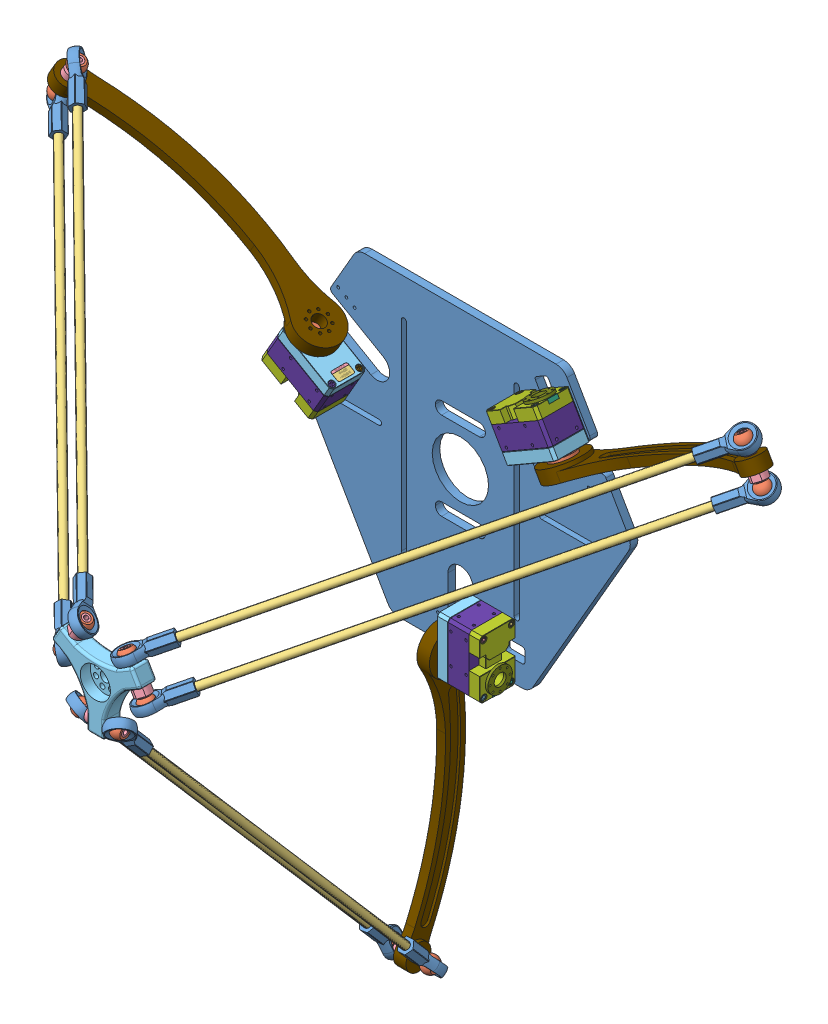
SolidWorks assembly Mat_1, configuration Default. Lengths in mm.
Overall size (587.7 511.52 315.27).
95 component instances, 23 part files, 90 mates.
Components (placement in the parent):
- base_XM430-1: base_XM430 [Default] at (94.6389 179.5874 188.3859) size (271.39 237.71 6)
- XM430-W350-R-1: XM430-W350-R [Default] at (171.6275 254.5304 208.1491) x (0 0 -1) z (0.5 -0.866025 0) size (28.5 46.5 41)
  - XM430-W350-R.step-1: XM430-W350-R.step [Default] at origin size (28.5 46.5 41)
    - Part 1.step-1: Part 1.step [Default] at (-0.4867 -0.6755 -0.5918) size (19.5 19.5 4)
    - Part 2.step-1: Part 2.step [Default] at (-0.4867 -0.6755 -0.5918) size (13.3 5.9 0.1)
    - Part 3.step-1: Part 3.step [Default] at (-0.4867 -0.6755 -0.5918) size (13.3 1.9 0.1)
    - Part 4.step-1: Part 4.step [Default] at (-0.4867 -0.6755 -0.5918) size (28.5 46.5 8.5)
    - Part 5.step-1: Part 5.step [Default] at (-0.4867 -0.6755 -0.5918) size (8 1.5 3)
    - Part 6.step-1: Part 6.step [Default] at (-0.4867 -0.6755 -0.5918) size (28.5 46.5 8.5)
    - Part 7.step-1: Part 7.step [Default] at (-0.4867 -0.6755 -0.5918) size (4 4 3.8)
    - Part 8.step-1: Part 8.step [Default] at (-0.4867 -0.6755 -0.5918) size (4 4 3.8)
    - Part 9.step-1: Part 9.step [Default] at (-0.4867 -0.6755 -0.5918) size (4 4 3.8)
    - Part 10.step-1: Part 10.step [Default] at (-0.4867 -0.6755 -0.5918) size (4 4 3.8)
    - Part 11.step-1: Part 11.step [Default] at (-0.4867 -0.6755 -0.5918) size (4 4 3.8)
    - Part 12.step-1: Part 12.step [Default] at (-0.4867 -0.6755 -0.5918) size (4 4 3.8)
    - Part 13.step-1: Part 13.step [Default] at (-0.4867 -0.6755 -0.5918) size (4 4 3.8)
    - Part 14.step-1: Part 14.step [Default] at (-0.4867 -0.6755 -0.5918) size (4 4 3.8)
    - Part 15.step-1: Part 15.step [Default] at (-0.4867 -0.6755 -0.5918) size (19.5 19.5 2)
    - Part 16.step-1: Part 16.step [Default] at (-0.4867 -0.6755 -0.5918) size (28.5 46.5 17)
- XM430-W350-R-2: XM430-W350-R [Default] at (-8.7579 208.79 208.1491) x (0 0 -1) z (0.5 0.866025 0) size (28.5 46.5 41)
  - XM430-W350-R.step-1: XM430-W350-R.step [Default] at origin size (28.5 46.5 41)
    - Part 1.step-1: Part 1.step [Default] at (-0.4867 -0.6755 -0.5918) size (19.5 19.5 4)
    - Part 2.step-1: Part 2.step [Default] at (-0.4867 -0.6755 -0.5918) size (13.3 5.9 0.1)
    - Part 3.step-1: Part 3.step [Default] at (-0.4867 -0.6755 -0.5918) size (13.3 1.9 0.1)
    - Part 4.step-1: Part 4.step [Default] at (-0.4867 -0.6755 -0.5918) size (28.5 46.5 8.5)
    - Part 5.step-1: Part 5.step [Default] at (-0.4867 -0.6755 -0.5918) size (8 1.5 3)
    - Part 6.step-1: Part 6.step [Default] at (-0.4867 -0.6755 -0.5918) size (28.5 46.5 8.5)
    - Part 7.step-1: Part 7.step [Default] at (-0.4867 -0.6755 -0.5918) size (4 4 3.8)
    - Part 8.step-1: Part 8.step [Default] at (-0.4867 -0.6755 -0.5918) size (4 4 3.8)
    - Part 9.step-1: Part 9.step [Default] at (-0.4867 -0.6755 -0.5918) size (4 4 3.8)
    - Part 10.step-1: Part 10.step [Default] at (-0.4867 -0.6755 -0.5918) size (4 4 3.8)
    - Part 11.step-1: Part 11.step [Default] at (-0.4867 -0.6755 -0.5918) size (4 4 3.8)
    - Part 12.step-1: Part 12.step [Default] at (-0.4867 -0.6755 -0.5918) size (4 4 3.8)
    - Part 13.step-1: Part 13.step [Default] at (-0.4867 -0.6755 -0.5918) size (4 4 3.8)
    - Part 14.step-1: Part 14.step [Default] at (-0.4867 -0.6755 -0.5918) size (4 4 3.8)
    - Part 15.step-1: Part 15.step [Default] at (-0.4867 -0.6755 -0.5918) size (19.5 19.5 2)
    - Part 16.step-1: Part 16.step [Default] at (-0.4867 -0.6755 -0.5918) size (28.5 46.5 17)
- XM430-W350-R-3: XM430-W350-R [Default] at (121.0471 75.4419 208.1491) x (0 0 -1) z (-1 0 0) size (28.5 46.5 41)
  - XM430-W350-R.step-1: XM430-W350-R.step [Default] at origin size (28.5 46.5 41)
    - Part 1.step-1: Part 1.step [Default] at (-0.4867 -0.6755 -0.5918) size (19.5 19.5 4)
    - Part 2.step-1: Part 2.step [Default] at (-0.4867 -0.6755 -0.5918) size (13.3 5.9 0.1)
    - Part 3.step-1: Part 3.step [Default] at (-0.4867 -0.6755 -0.5918) size (13.3 1.9 0.1)
    - Part 4.step-1: Part 4.step [Default] at (-0.4867 -0.6755 -0.5918) size (28.5 46.5 8.5)
    - Part 5.step-1: Part 5.step [Default] at (-0.4867 -0.6755 -0.5918) size (8 1.5 3)
    - Part 6.step-1: Part 6.step [Default] at (-0.4867 -0.6755 -0.5918) size (28.5 46.5 8.5)
    - Part 7.step-1: Part 7.step [Default] at (-0.4867 -0.6755 -0.5918) size (4 4 3.8)
    - Part 8.step-1: Part 8.step [Default] at (-0.4867 -0.6755 -0.5918) size (4 4 3.8)
    - Part 9.step-1: Part 9.step [Default] at (-0.4867 -0.6755 -0.5918) size (4 4 3.8)
    - Part 10.step-1: Part 10.step [Default] at (-0.4867 -0.6755 -0.5918) size (4 4 3.8)
    - Part 11.step-1: Part 11.step [Default] at (-0.4867 -0.6755 -0.5918) size (4 4 3.8)
    - Part 12.step-1: Part 12.step [Default] at (-0.4867 -0.6755 -0.5918) size (4 4 3.8)
    - Part 13.step-1: Part 13.step [Default] at (-0.4867 -0.6755 -0.5918) size (4 4 3.8)
    - Part 14.step-1: Part 14.step [Default] at (-0.4867 -0.6755 -0.5918) size (4 4 3.8)
    - Part 15.step-1: Part 15.step [Default] at (-0.4867 -0.6755 -0.5918) size (19.5 19.5 2)
    - Part 16.step-1: Part 16.step [Default] at (-0.4867 -0.6755 -0.5918) size (28.5 46.5 17)
- link1-1: link1 [Default] at (196.1389 234.7244 208.6359) x (0.86024 0.49666 0.115398) z (-0.5 0.866025 0) size (227.5 42.75 10)
- link1-2: link1 [Default] at (-3.861 239.9205 208.6359) x (-0.857709 0.495198 0.138254) z (-0.5 -0.866025 0) size (227.5 42.75 10)
- link1-3: link1 [Default] at (91.6389 64.1174 208.6359) x (0 -0.991091 0.133184) z (1 0 0) size (227.5 42.75 10)
- KCRM-06-01-1: KCRM-06-01 [Default] at (111.0291 -111.4679 254.479) x (0.999256 0.027885 -0.026646) z (-0.038396 0.653635 -0.755836) size (20 40 10)
- KCRM-06 -02-1: KCRM-06 -02 [Default] at (111.1389 -134.1568 234.8524) x (0 0.894063 -0.447941) z (1 0 0) size (12.7 12.7 9)
- lower_link-1: lower_link [Default] at (109.8086 140.7569 472.661) x (0.999256 0.027889 -0.02665) z (-0.038401 0.653634 -0.755836) size (6 350 6)
- KCRM-06-01-2: KCRM-06-01 [Default] at (109.869 128.278 461.8664) x (-0.815543 -0.380849 0.435711) z (-0.578685 0.531949 -0.618186) size (20 40 10)
- KCRM-06 -02-2: KCRM-06 -02 [Default] at (109.7592 150.9669 481.4929) x (0 -0.000388 -1) z (1 0 0) size (12.7 12.7 9)
- KCRM-06 -02-3: KCRM-06 -02 [Default] at (131.8069 179.6285 481.4929) x (0.718188 0.414646 -0.558815) z (0.5 -0.866025 0) size (12.7 12.7 9)
- KCRM-06-01-3: KCRM-06-01 [Default] at (151.058 191.161 461.5832) x (-0.649036 -0.188836 -0.736948) z (-0.408619 0.903639 0.128325) size (20 40 10)
- lower_link-2: lower_link [Default] at (140.4699 184.8181 472.5336) x (0.425942 0.540972 0.725206) z (-0.637802 0.748045 -0.183403) size (6 350 6)
- KCRM-06-01-4: KCRM-06-01 [Default] at (354.4777 313.0217 251.2041) x (0.761869 -0.418986 0.493971) z (0.088171 0.822601 0.561741) size (20 40 10)
- KCRM-06 -02-4: KCRM-06 -02 [Default] at (373.7288 324.5543 231.2944) x (0.749997 0.433011 -0.500006) z (0.5 -0.866025 0) size (12.7 12.7 9)
- KCRM-06 -02-5: KCRM-06 -02 [Default] at (80.6389 -134.1568 234.8524) x (0 0.823718 0.567) z (-1 0 0) size (12.7 12.7 9)
- KCRM-06-01-5: KCRM-06-01 [Default] at (80.5291 -111.4679 254.479) x (-0.594832 0.524249 -0.609375) z (-0.803842 -0.391381 0.447951) size (20 40 10)
- lower_link-3: lower_link [Default] at (80.5895 -123.9468 243.6844) x (0.408342 -0.596063 0.691351) z (-0.912822 -0.269675 0.306646) size (6 350 6)
- KCRM-06-01-6: KCRM-06-01 [Default] at (79.369 128.278 461.8664) x (0.937628 -0.224829 0.265154) z (-0.347622 -0.614384 0.708302) size (20 40 10)
- KCRM-06 -02-6: KCRM-06 -02 [Default] at (79.2592 150.9669 481.4929) x (0 -0.747405 0.664368) z (1 0 0) size (12.7 12.7 9)
- KCRM-06 -02-7: KCRM-06 -02 [Default] at (-169.9531 348.5156 235.8668) x (0.75 -0.433013 -0.5) z (0.5 0.866025 0) size (12.7 12.7 9)
- KCRM-06-01-7: KCRM-06-01 [Default] at (-150.0064 337.5572 255.4127) x (0.080666 0.902278 0.423542) z (-0.74257 -0.229054 0.629384) size (20 40 10)
- lower_link-4: lower_link [Default] at (-160.9771 343.5843 244.6625) x (0.261217 -0.703473 -0.660977) z (-0.699774 -0.609669 0.372317) size (6 350 6)
- KCRM-06-01-8: KCRM-06-01 [Default] at (60.7647 221.7638 461.9471) x (0.258788 -0.705584 -0.659682) z (-0.700676 -0.607226 0.374608) size (20 40 10)
- KCRM-06 -02-8: KCRM-06 -02 [Default] at (80.7114 210.8054 481.4929) x (-0.584131 0.337248 0.738278) z (0.5 0.866025 0) size (12.7 12.7 9)
- KCRM-06 -02-9: KCRM-06 -02 [Default] at (116.5569 206.0422 481.4929) x (-0.850143 -0.490831 0.190634) z (0.5 -0.866025 0) size (12.7 12.7 9)
- KCRM-06-01-9: KCRM-06-01 [Default] at (135.808 217.5748 461.5832) x (-0.645888 -0.195752 -0.737909) z (-0.413578 0.902166 0.122676) size (20 40 10)
- lower_link-5: lower_link [Default] at (125.2199 211.2319 472.5336) x (0.724752 -0.587022 0.360749) z (0.250902 0.71248 0.655301) size (6 350 6)
- KCRM-06-01-10: KCRM-06-01 [Default] at (339.2277 339.4355 251.2041) x (0.766483 -0.351736 0.537387) z (0.026851 0.853524 0.520361) size (20 40 10)
- KCRM-06 -02-10: KCRM-06 -02 [Default] at (358.4788 350.968 231.2944) x (0.452431 0.261211 -0.852687) z (-0.5 0.866025 0) size (12.7 12.7 9)
- KCRM-06 -02-11: KCRM-06 -02 [Default] at (-185.2031 322.1018 235.8668) x (0.80068 -0.462273 0.381072) z (-0.5 -0.866025 0) size (12.7 12.7 9)
- KCRM-06-01-11: KCRM-06-01 [Default] at (-165.2564 311.1434 255.4127) x (0.47625 0.879282 0.00695) z (-0.575416 0.305669 0.758593) size (20 40 10)
- lower_link-6: lower_link [Default] at (-176.2271 317.1705 244.6625) x (0.552929 -0.345741 -0.758111) z (-0.502182 -0.864311 0.027908) size (6 350 6)
- KCRM-06-01-12: KCRM-06-01 [Default] at (45.5147 195.35 461.9471) x (-0.083981 -0.903292 -0.420726) z (-0.742203 -0.225022 0.631269) size (20 40 10)
- KCRM-06 -02-12: KCRM-06 -02 [Default] at (65.4614 184.3916 481.4929) x (0.858883 -0.495876 -0.12817) z (-0.5 -0.866025 0) size (12.7 12.7 9)
- custom_pin-1: custom_pin [Default] at (360.2288 347.9369 231.2944) x (0.749997 0.433011 -0.500006) z (0.5 -0.866025 0) size (12 10.5 39.5)
- custom_pin-2: custom_pin [Default] at (-183.4531 325.1329 235.8668) x (-0.261078 0.150734 -0.953477) z (0.5 0.866025 0) size (12 10.5 39.5)
- custom_pin-3: custom_pin [Default] at (107.6389 -134.1568 234.8524) x (0 0.792636 -0.609695) z (-1 0 0) size (12 10.5 39.5)
- New_end_effector_holder-1: New_end_effector_holder [Default] at (97.2592 180.4669 474.4929) x (0.5 0.866025 0) z (0 0 1) size (69.62 60.83 14.23)
- custom_pin-4: custom_pin [Default] at (67.2114 187.4227 481.4929) x (-0.749064 0.432472 -0.501868) z (0.5 0.866025 0) size (12 10.5 39.5)
- custom_pin-5: custom_pin [Default] at (106.2592 150.9669 481.4929) x (0 -0.426843 -0.904326) z (-1 0 0) size (12 10.5 39.5)
- custom_pin-6: custom_pin [Default] at (118.3069 203.0112 481.4929) x (0.758252 0.437777 -0.48312) z (0.5 -0.866025 0) size (12 10.5 39.5)
Mates (geometry in assembly coordinates):
- Concentric1: concentric aligned: cylinder of base_XM430-1 through (180.6748 253.509 184.3859) axis (0 0 1) radius 1.6; cylinder of XM430-W350-R-1/XM430-W350-R.step-1/Part 16.step-1 through (180.6748 253.509 197.3859) axis (0 0 1) radius 1
- Concentric2: concentric aligned: cylinder of base_XM430-1 through (153.8902 251.9013 184.3859) axis (0 0 1) radius 1.6; cylinder of XM430-W350-R-1/XM430-W350-R.step-1/Part 16.step-1 through (153.8902 251.9013 197.3859) axis (0 0 1) radius 1
- Coincident1: coincident anti-aligned: plane of base_XM430-1 through (94.6389 179.5874 194.3859) normal (0 0 1); plane of XM430-W350-R-1/XM430-W350-R.step-1/Part 16.step-1 through (186.6317 273.6913 194.3859) normal (0 0 -1)
- Concentric3: concentric aligned: cylinder of base_XM430-1 through (115.6389 68.1174 184.3859) axis (0 0 1) radius 1.6; cylinder of XM430-W350-R-3/XM430-W350-R.step-1/Part 16.step-1 through (115.6389 68.1174 197.3859) axis (0 0 1) radius 1
- Concentric4: concentric aligned: cylinder of base_XM430-1 through (127.6389 92.1174 184.3859) axis (0 0 1) radius 1.6; cylinder of XM430-W350-R-3/XM430-W350-R.step-1/Part 16.step-1 through (127.6389 92.1174 197.3859) axis (0 0 1) radius 1
- Coincident2: coincident anti-aligned: plane of base_XM430-1 through (94.6389 179.5874 194.3859) normal (0 0 1); plane of XM430-W350-R-3/XM430-W350-R.step-1/Part 16.step-1 through (130.1389 52.8674 194.3859) normal (0 0 -1)
- Concentric5: concentric aligned: cylinder of base_XM430-1 through (-12.3969 217.1359 184.3859) axis (0 0 1) radius 1.6; cylinder of XM430-W350-R-2/XM430-W350-R.step-1/Part 16.step-1 through (-12.3969 217.1359 197.3859) axis (0 0 1) radius 1
- Concentric6: concentric aligned: cylinder of base_XM430-1 through (2.3877 194.7436 184.3859) axis (0 0 1) radius 1.6; cylinder of XM430-W350-R-2/XM430-W350-R.step-1/Part 16.step-1 through (2.3877 194.7436 197.3859) axis (0 0 1) radius 1
- Coincident3: coincident anti-aligned: plane of base_XM430-1 through (94.6389 179.5874 194.3859) normal (0 0 1); plane of XM430-W350-R-2/XM430-W350-R.step-1/Part 16.step-1 through (-32.8538 212.2035 194.3859) normal (0 0 -1)
- Concentric7: concentric aligned: cylinder of XM430-W350-R-1/XM430-W350-R.step-1/Part 1.step-1 through (192.1389 241.6526 208.6359) axis (0.5 -0.866025 0) radius 4; cylinder of link1-1 through (191.1389 243.3846 208.6359) axis (0.5 -0.866025 0) radius 5
- Concentric8: concentric aligned: cylinder of XM430-W350-R-3/XM430-W350-R.step-1/Part 1.step-1 through (99.6389 64.1174 208.6359) axis (-1 0 0) radius 4; cylinder of link1-3 through (101.6389 64.1174 208.6359) axis (-1 0 0) radius 5
- Coincident5: coincident anti-aligned: plane of XM430-W350-R-1/XM430-W350-R.step-1/Part 1.step-1 through (191.1389 243.3846 208.6359) normal (0.5 -0.866025 0); plane of link1-1 through (306.2269 309.8307 367.194) normal (-0.5 0.866025 0)
- Coincident6: coincident anti-aligned: plane of XM430-W350-R-3/XM430-W350-R.step-1/Part 1.step-1 through (101.6389 64.1174 208.6359) normal (-1 0 0); plane of link1-3 through (101.6389 -65.9114 369.5505) normal (1 0 0)
- Concentric9: concentric aligned: cylinder of XM430-W350-R-2/XM430-W350-R.step-1/Part 1.step-1 through (-7.861 232.9923 208.6359) axis (0.5 0.866025 0) radius 4; cylinder of link1-2 through (-8.861 231.2603 208.6359) axis (0.5 0.866025 0) radius 5
- Coincident7: coincident anti-aligned: plane of XM430-W350-R-2/XM430-W350-R.step-1/Part 1.step-1 through (-8.861 231.2603 208.6359) normal (0.5 0.866025 0); plane of link1-2 through (-120.7546 295.862 370.2138) normal (-0.5 -0.866025 0)
- Concentric10: concentric anti-aligned: cylinder of KCRM-06-01-1 through (111.0291 -111.4679 254.479) axis (0.00366 -0.756296 -0.654219) radius 2.4585; cylinder of lower_link-1 through (111.0895 -123.9468 243.6844) axis (-0.00366 0.756296 0.654219) radius 3
- Concentric11: concentric aligned: cylinder of lower_link-1 through (111.0895 -123.9468 243.6844) axis (-0.00366 0.756296 0.654219) radius 3; cylinder of KCRM-06-01-2 through (109.869 128.278 461.8664) axis (-0.00366 0.756296 0.654219) radius 2.4585
- Coincident8: coincident anti-aligned: plane of lower_link-1 through (109.869 128.278 461.8664) normal (-0.00366 0.756296 0.654219); plane of KCRM-06-01-2 through (109.869 128.278 461.8664) normal (0.00366 -0.756296 -0.654219)
- Coincident9: coincident anti-aligned: plane of KCRM-06-01-1 through (111.0291 -111.4679 254.479) normal (-0.00366 0.756296 0.654219); plane of lower_link-1 through (111.0291 -111.4679 254.479) normal (0.00366 -0.756296 -0.654219)
- Coincident10: coincident: point of KCRM-06-01-1; point of KCRM-06 -02-1
- Coincident11: coincident: point of KCRM-06-01-2; point of KCRM-06 -02-2
- Coincident12: coincident anti-aligned: plane of KCRM-06-01-3 through (151.058 191.161 461.5832) normal (0.641703 0.384419 -0.663657); plane of lower_link-2 through (151.058 191.161 461.5832) normal (-0.641703 -0.384419 0.663657)
- Concentric12: concentric anti-aligned: cylinder of lower_link-2 through (365.0658 319.3646 240.2537) axis (-0.641703 -0.384419 0.663657) radius 3; cylinder of KCRM-06-01-4 through (354.4777 313.0217 251.2041) axis (0.641703 0.384419 -0.663657) radius 2.4585
- Concentric13: concentric aligned: cylinder of KCRM-06-01-3 through (151.058 191.161 461.5832) axis (-0.641703 -0.384419 0.663657) radius 2.4585; cylinder of lower_link-2 through (365.0658 319.3646 240.2537) axis (-0.641703 -0.384419 0.663657) radius 3
- Coincident13: coincident: point of KCRM-06 -02-3; point of KCRM-06-01-3
- Coincident14: coincident anti-aligned: plane of lower_link-2 through (354.4777 313.0217 251.2041) normal (0.641703 0.384419 -0.663657); plane of KCRM-06-01-4 through (354.4777 313.0217 251.2041) normal (-0.641703 -0.384419 0.663657)
- Coincident15: coincident: point of KCRM-06-01-4; point of KCRM-06 -02-4
- Coincident16: coincident anti-aligned: plane of KCRM-06-01-5 through (80.5291 -111.4679 254.479) normal (-0.00366 0.756296 0.654219); plane of lower_link-3 through (80.5291 -111.4679 254.479) normal (0.00366 -0.756296 -0.654219)
- Concentric14: concentric anti-aligned: cylinder of lower_link-3 through (79.3086 140.7569 472.661) axis (0.00366 -0.756296 -0.654219) radius 3; cylinder of KCRM-06-01-6 through (79.369 128.278 461.8664) axis (-0.00366 0.756296 0.654219) radius 2.4585
- Concentric15: concentric aligned: cylinder of KCRM-06-01-5 through (80.5291 -111.4679 254.479) axis (0.00366 -0.756296 -0.654219) radius 2.4585; cylinder of lower_link-3 through (79.3086 140.7569 472.661) axis (0.00366 -0.756296 -0.654219) radius 3
- Coincident17: coincident: point of KCRM-06 -02-5; point of KCRM-06-01-5
- Coincident18: coincident anti-aligned: plane of lower_link-3 through (79.369 128.278 461.8664) normal (-0.00366 0.756296 0.654219); plane of KCRM-06-01-6 through (79.369 128.278 461.8664) normal (0.00366 -0.756296 -0.654219)
- Coincident19: coincident: point of KCRM-06-01-6; point of KCRM-06 -02-6
- Coincident20: coincident anti-aligned: plane of KCRM-06-01-7 through (-150.0064 337.5572 255.4127) normal (0.664893 -0.365279 0.651528); plane of lower_link-4 through (-150.0064 337.5572 255.4127) normal (-0.664893 0.365279 -0.651528)
- Concentric16: concentric anti-aligned: cylinder of lower_link-4 through (71.7354 215.7367 472.6973) axis (-0.664893 0.365279 -0.651528) radius 3; cylinder of KCRM-06-01-8 through (60.7647 221.7638 461.9471) axis (0.664893 -0.365279 0.651528) radius 2.4585
- Concentric17: concentric aligned: cylinder of KCRM-06-01-7 through (-150.0064 337.5572 255.4127) axis (-0.664893 0.365279 -0.651528) radius 2.4585; cylinder of lower_link-4 through (71.7354 215.7367 472.6973) axis (-0.664893 0.365279 -0.651528) radius 3
- Coincident21: coincident: point of KCRM-06 -02-7; point of KCRM-06-01-7
- Coincident22: coincident anti-aligned: plane of lower_link-4 through (60.7647 221.7638 461.9471) normal (0.664893 -0.365279 0.651528); plane of KCRM-06-01-8 through (60.7647 221.7638 461.9471) normal (-0.664893 0.365279 -0.651528)
- Coincident23: coincident: point of KCRM-06-01-8; point of KCRM-06 -02-8
- Coincident24: coincident anti-aligned: plane of KCRM-06-01-9 through (135.808 217.5748 461.5832) normal (0.641703 0.384419 -0.663657); plane of lower_link-5 through (135.808 217.5748 461.5832) normal (-0.641703 -0.384419 0.663657)
- Concentric18: concentric anti-aligned: cylinder of lower_link-5 through (349.8158 345.7784 240.2537) axis (-0.641703 -0.384419 0.663657) radius 3; cylinder of KCRM-06-01-10 through (339.2277 339.4355 251.2041) axis (0.641703 0.384419 -0.663657) radius 2.4585
- Concentric19: concentric aligned: cylinder of KCRM-06-01-9 through (135.808 217.5748 461.5832) axis (-0.641703 -0.384419 0.663657) radius 2.4585; cylinder of lower_link-5 through (349.8158 345.7784 240.2537) axis (-0.641703 -0.384419 0.663657) radius 3
- Coincident25: coincident: point of KCRM-06 -02-9; point of KCRM-06-01-9
- Coincident26: coincident anti-aligned: plane of lower_link-5 through (339.2277 339.4355 251.2041) normal (0.641703 0.384419 -0.663657); plane of KCRM-06-01-10 through (339.2277 339.4355 251.2041) normal (-0.641703 -0.384419 0.663657)
- Coincident27: coincident: point of KCRM-06-01-10; point of KCRM-06 -02-10
- Coincident28: coincident anti-aligned: plane of KCRM-06-01-11 through (-165.2564 311.1434 255.4127) normal (0.664893 -0.365279 0.651528); plane of lower_link-6 through (-165.2564 311.1434 255.4127) normal (-0.664893 0.365279 -0.651528)
- Concentric20: concentric anti-aligned: cylinder of lower_link-6 through (56.4854 189.3229 472.6973) axis (-0.664893 0.365279 -0.651528) radius 3; cylinder of KCRM-06-01-12 through (45.5147 195.35 461.9471) axis (0.664893 -0.365279 0.651528) radius 2.4585
- Concentric21: concentric aligned: cylinder of KCRM-06-01-11 through (-165.2564 311.1434 255.4127) axis (-0.664893 0.365279 -0.651528) radius 2.4585; cylinder of lower_link-6 through (56.4854 189.3229 472.6973) axis (-0.664893 0.365279 -0.651528) radius 3
- Coincident29: coincident: point of KCRM-06 -02-11; point of KCRM-06-01-11
- Coincident30: coincident anti-aligned: plane of lower_link-6 through (45.5147 195.35 461.9471) normal (0.664893 -0.365279 0.651528); plane of KCRM-06-01-12 through (45.5147 195.35 461.9471) normal (-0.664893 0.365279 -0.651528)
- Coincident31: coincident: point of KCRM-06-01-12; point of KCRM-06 -02-12
- Concentric22: concentric anti-aligned: cylinder of link1-1 through (363.2288 342.7408 231.2944) axis (0.5 -0.866025 0) radius 4; cylinder of custom_pin-1 through (368.2288 334.0805 231.2944) axis (-0.5 0.866025 0) radius 4
- Coincident32: coincident anti-aligned: plane of link1-1 through (311.2269 301.1704 367.194) normal (0.5 -0.866025 0); plane of custom_pin-1 through (368.2288 334.0805 231.2944) normal (-0.5 0.866025 0)
- Concentric24: concentric anti-aligned: cylinder of link1-3 through (101.6389 -134.1568 234.8524) axis (-1 0 0) radius 4; cylinder of custom_pin-3 through (91.6389 -134.1568 234.8524) axis (1 0 0) radius 4
- Coincident33: coincident anti-aligned: plane of link1-3 through (91.6389 -65.9114 369.5505) normal (-1 0 0); plane of custom_pin-3 through (91.6389 -134.1568 234.8524) normal (1 0 0)
- Concentric25: concentric anti-aligned: cylinder of link1-2 through (-180.4531 330.329 235.8668) axis (0.5 0.866025 0) radius 4; cylinder of custom_pin-2 through (-175.4531 338.9893 235.8668) axis (-0.5 -0.866025 0) radius 4
- Coincident34: coincident anti-aligned: plane of link1-2 through (-115.7546 304.5223 370.2138) normal (0.5 0.866025 0); plane of custom_pin-2 through (-175.4531 338.9893 235.8668) normal (-0.5 -0.866025 0)
- Concentric26: concentric anti-aligned: cylinder of KCRM-06 -02-10 through (360.7288 347.0709 231.2944) axis (-0.5 0.866025 0) radius 3; cylinder of custom_pin-1 through (355.7288 355.7312 231.2944) axis (0.5 -0.866025 0) radius 3
- Concentric27: concentric anti-aligned: cylinder of KCRM-06 -02-4 through (371.4788 328.4514 231.2944) axis (0.5 -0.866025 0) radius 3; cylinder of custom_pin-1 through (376.7288 319.3581 231.2944) axis (-0.5 0.866025 0) radius 3
- Concentric28: concentric anti-aligned: cylinder of KCRM-06 -02-1 through (106.6389 -134.1568 234.8524) axis (1 0 0) radius 3; cylinder of custom_pin-3 through (116.6389 -134.1568 234.8524) axis (-1 0 0) radius 3
- Concentric29: concentric anti-aligned: cylinder of KCRM-06 -02-5 through (85.1389 -134.1568 234.8524) axis (-1 0 0) radius 3; cylinder of custom_pin-3 through (74.6389 -134.1568 234.8524) axis (1 0 0) radius 3
- Concentric30: concentric anti-aligned: cylinder of KCRM-06 -02-11 through (-182.9531 325.9989 235.8668) axis (-0.5 -0.866025 0) radius 3; cylinder of custom_pin-2 through (-187.9531 317.3386 235.8668) axis (0.5 0.866025 0) radius 3
- Concentric31: concentric anti-aligned: cylinder of KCRM-06 -02-7 through (-172.2031 344.6184 235.8668) axis (0.5 0.866025 0) radius 3; cylinder of custom_pin-2 through (-166.9531 353.7117 235.8668) axis (-0.5 -0.866025 0) radius 3
- Concentric32: concentric aligned: cylinder of New_end_effector_holder-1 through (89.1174 225.3649 481.4929) axis (-0.5 -0.866025 0) radius 4; cylinder of custom_pin-4 through (75.2114 201.2791 481.4929) axis (-0.5 -0.866025 0) radius 4
- Coincident41: coincident anti-aligned: plane of New_end_effector_holder-1 through (68.7162 205.0291 488.4929) normal (0.5 0.866025 0); plane of custom_pin-4 through (75.2114 201.2791 481.4929) normal (-0.5 -0.866025 0)
- Concentric33: concentric aligned: cylinder of New_end_effector_holder-1 through (47.8094 150.9669 481.4929) axis (1 0 0) radius 4; cylinder of custom_pin-5 through (90.2592 150.9669 481.4929) axis (1 0 0) radius 4
- Coincident42: coincident anti-aligned: plane of New_end_effector_holder-1 through (90.2592 143.4669 488.4929) normal (-1 0 0); plane of custom_pin-5 through (90.2592 150.9669 481.4929) normal (1 0 0)
- Concentric34: concentric aligned: cylinder of New_end_effector_holder-1 through (142.3291 161.4036 481.4929) axis (-0.5 0.866025 0) radius 4; cylinder of custom_pin-6 through (126.3069 189.1548 481.4929) axis (-0.5 0.866025 0) radius 4
- Coincident43: coincident anti-aligned: plane of New_end_effector_holder-1 through (132.8021 192.9048 488.4929) normal (0.5 -0.866025 0); plane of custom_pin-6 through (126.3069 189.1548 481.4929) normal (-0.5 0.866025 0)
- Concentric35: concentric anti-aligned: cylinder of KCRM-06 -02-3 through (129.5569 183.5256 481.4929) axis (0.5 -0.866025 0) radius 3; cylinder of custom_pin-6 through (134.8069 174.4323 481.4929) axis (-0.5 0.866025 0) radius 3
- Concentric36: concentric aligned: cylinder of KCRM-06 -02-9 through (114.3069 209.9394 481.4929) axis (0.5 -0.866025 0) radius 3; cylinder of custom_pin-6 through (113.8069 210.8054 481.4929) axis (0.5 -0.866025 0) radius 3
- Concentric37: concentric anti-aligned: cylinder of KCRM-06 -02-8 through (78.4614 206.9083 481.4929) axis (0.5 0.866025 0) radius 3; cylinder of custom_pin-4 through (83.7114 216.0015 481.4929) axis (-0.5 -0.866025 0) radius 3
- Concentric38: concentric anti-aligned: cylinder of KCRM-06 -02-12 through (67.7114 188.2887 481.4929) axis (-0.5 -0.866025 0) radius 3; cylinder of custom_pin-4 through (62.7114 179.6285 481.4929) axis (0.5 0.866025 0) radius 3
- Concentric39: concentric aligned: cylinder of KCRM-06 -02-6 through (74.7592 150.9669 481.4929) axis (1 0 0) radius 3; cylinder of custom_pin-5 through (73.2592 150.9669 481.4929) axis (1 0 0) radius 3
- Concentric40: concentric anti-aligned: cylinder of KCRM-06 -02-2 through (105.2592 150.9669 481.4929) axis (1 0 0) radius 3; cylinder of custom_pin-5 through (115.2592 150.9669 481.4929) axis (-1 0 0) radius 3
- Coincident50: coincident aligned: plane of KCRM-06 -02-5 through (76.1389 -131.6165 231.162) normal (-1 0 0); plane of custom_pin-3 through (76.1389 -134.1568 234.8524) normal (-1 0 0)
- Coincident51: coincident aligned: plane of KCRM-06 -02-1 through (115.6389 -132.15 238.8581) normal (1 0 0); plane of custom_pin-3 through (115.6389 -134.1568 234.8524) normal (1 0 0)
- Coincident52: coincident aligned: plane of KCRM-06 -02-11 through (-188.9317 319.0583 240.009) normal (-0.5 -0.866025 0); plane of custom_pin-2 through (-187.4531 318.2047 235.8668) normal (-0.5 -0.866025 0)
- Coincident53: coincident aligned: plane of KCRM-06 -02-7 through (-169.6431 353.5327 231.9869) normal (0.5 0.866025 0); plane of custom_pin-2 through (-167.7031 352.4127 235.8668) normal (0.5 0.866025 0)
- Coincident54: coincident aligned: plane of KCRM-06 -02-10 through (352.9204 352.955 228.9538) normal (-0.5 0.866025 0); plane of custom_pin-1 through (356.2288 354.8651 231.2944) normal (-0.5 0.866025 0)
- Coincident55: coincident aligned: plane of KCRM-06 -02-4 through (377.9188 321.7772 235.1744) normal (0.5 -0.866025 0); plane of custom_pin-1 through (375.9788 320.6571 231.2944) normal (0.5 -0.866025 0)
- Coincident56: coincident aligned: plane of KCRM-06 -02-3 through (136.2251 176.9832 485.2084) normal (0.5 -0.866025 0); plane of custom_pin-6 through (134.0569 175.7314 481.4929) normal (0.5 -0.866025 0)
- Coincident57: coincident aligned: plane of KCRM-06 -02-2 through (114.2592 155.4472 481.4912) normal (1 0 0); plane of custom_pin-5 through (114.2592 150.9669 481.4929) normal (1 0 0)
- Coincident58: coincident aligned: plane of KCRM-06 -02-6 through (74.7592 148.9738 479.2507) normal (-1 0 0); plane of custom_pin-5 through (74.7592 150.9669 481.4929) normal (-1 0 0)
- Coincident59: coincident aligned: plane of KCRM-06 -02-12 through (63.7087 180.2074 485.9362) normal (-0.5 -0.866025 0); plane of custom_pin-4 through (63.2114 180.4945 481.4929) normal (-0.5 -0.866025 0)
- Coincident60: coincident aligned: plane of KCRM-06 -02-8 through (85.8259 213.0487 484.5148) normal (0.5 0.866025 0); plane of custom_pin-4 through (82.9614 214.7025 481.4929) normal (0.5 0.866025 0)
- Coincident61: coincident aligned: plane of KCRM-06 -02-9 through (113.8117 209.6534 478.548) normal (-0.5 0.866025 0); plane of custom_pin-6 through (114.3069 209.9394 481.4929) normal (-0.5 0.866025 0)
- Parallel1: parallel aligned: cylinder of lower_link-2 through (365.0658 319.3646 240.2537) axis (-0.641703 -0.384419 0.663657) radius 3; cylinder of lower_link-5 through (349.8158 345.7784 240.2537) axis (-0.641703 -0.384419 0.663657) radius 3
- Parallel2: parallel aligned: cylinder of lower_link-4 through (71.7354 215.7367 472.6973) axis (-0.664893 0.365279 -0.651528) radius 3; cylinder of lower_link-6 through (56.4854 189.3229 472.6973) axis (-0.664893 0.365279 -0.651528) radius 3
- Parallel3: parallel anti-aligned: cylinder of lower_link-1 through (111.0895 -123.9468 243.6844) axis (-0.00366 0.756296 0.654219) radius 3; cylinder of lower_link-3 through (79.3086 140.7569 472.661) axis (0.00366 -0.756296 -0.654219) radius 3
